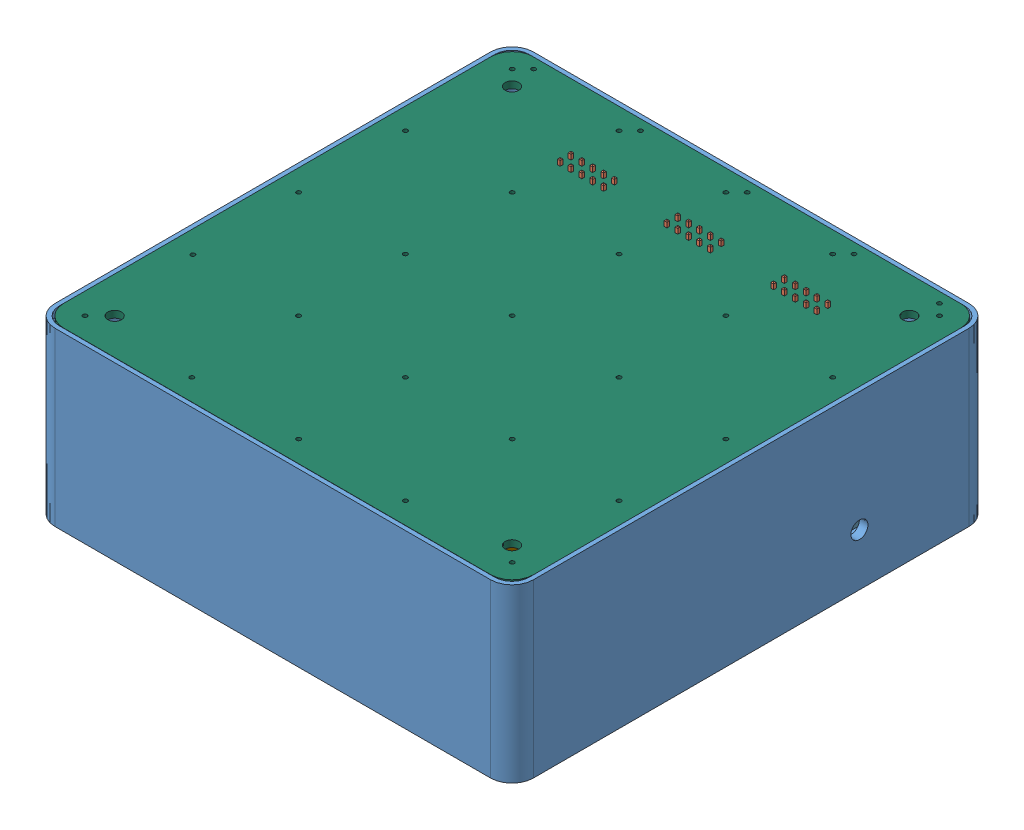
SolidWorks assembly Assembly_final, configuration Default. Lengths in mm.
Overall size (112 41.55 112).
151 component instances, 15 part files, 5 mates.
Components (placement in the parent):
- Enclosure_final-1: Enclosure_final [Default] at (47.994 33.4728 84.6976) size (112 40.2 112)
- LED_Cube_5X5X5.step-1: LED_Cube_5X5X5.step [Default] at (151.994 40.4728 -67.3024) x (0 0 1) z (0 1 0) size (100 101 23.3)
  - IDC-Header_2x05_P2.54mm_Vertical.step-1: IDC-Header_2x05_P2.54mm_Vertical.step [Default] at (191.25 -123 1.65) size (9.1 20.36 12.1)
    - SOLID.step-1: SOLID.step [Default] at origin size (9.1 20.36 12.1)
  - 61201023021_(rev1).step-1: 61201023021_(rev1).step [Default] at (192.25 -128 11.15) x (0 1 0) z (0 0 -1) size (17.38 6.86 15.7)
    - COMPOUND.step-1: COMPOUND.step [Default] at origin size (17.38 6.86 15.7)
  - C_Disc_D3.0mm_W1.6mm_P2.50mm.step-1: C_Disc_D3.0mm_W1.6mm_P2.50mm.step [Default] at (110.5 -105.5 1.65) x (-1 0 0) z (0 0 1) size (3.5 1.6 5.1)
    - SOLID-0.step-1: SOLID-0.step [Default] at origin size (3.5 1.6 5.1)
  - C_Disc_D3.0mm_W1.6mm_P2.50mm.step-2: C_Disc_D3.0mm_W1.6mm_P2.50mm.step [Default] at (110.5 -100.62 1.65) x (-1 0 0) z (0 0 1) size (3.5 1.6 5.1)
    - SOLID-0.step-1: SOLID-0.step [Default] at origin size (3.5 1.6 5.1)
  - CP_Radial_Tantal_D5.0mm_P5.00mm.step-1: CP_Radial_Tantal_D5.0mm_P5.00mm.step [Default] at (114 -90 1.65) x (0 -1 0) z (0 0 1) size (6 5 10.1)
    - SOLID-1.step-1: SOLID-1.step [Default] at origin size (6 5 10.1)
  - CP_Radial_Tantal_D5.0mm_P5.00mm.step-2: CP_Radial_Tantal_D5.0mm_P5.00mm.step [Default] at (153.75 -61.45 1.65) x (0 -1 0) z (0 0 1) size (6 5 10.1)
    - SOLID-1.step-1: SOLID-1.step [Default] at origin size (6 5 10.1)
  - CP_Radial_Tantal_D5.0mm_P5.00mm.step-3: CP_Radial_Tantal_D5.0mm_P5.00mm.step [Default] at (153.75 -87.2 1.65) x (0 -1 0) z (0 0 1) size (6 5 10.1)
    - SOLID-1.step-1: SOLID-1.step [Default] at origin size (6 5 10.1)
  - CP_Radial_Tantal_D5.0mm_P5.00mm.step-4: CP_Radial_Tantal_D5.0mm_P5.00mm.step [Default] at (153.75 -112.95 1.65) x (0 -1 0) z (0 0 1) size (6 5 10.1)
    - SOLID-1.step-1: SOLID-1.step [Default] at origin size (6 5 10.1)
  - CP_Radial_Tantal_D5.0mm_P5.00mm.step-5: CP_Radial_Tantal_D5.0mm_P5.00mm.step [Default] at (153.75 -138.2 1.65) x (0 -1 0) z (0 0 1) size (6 5 10.1)
    - SOLID-1.step-1: SOLID-1.step [Default] at origin size (6 5 10.1)
  - K375A_-PCM_DC_Power_Jack_2mm_Pin.step-1: K375A_-PCM_DC_Power_Jack_2mm_Pin.step [Default] at (108.0498 -117.25 1.65) x (0 1 0) z (0 0 1) size (9.8 14.5 16.1)
    - SOLID-2.step-1: SOLID-2.step [Default] at origin size (9.8 14.5 16.1)
  - TO-92_Inline.step-1: TO-92_Inline.step [Default] at (112.25 -143.25 1.65) x (0 1 0) z (0 0 1) size (4.83 3.75 9.8)
    - SOLID-3.step-1: SOLID-3.step [Default] at origin size (4.83 3.75 9.8)
  - TO-92_Inline.step-2: TO-92_Inline.step [Default] at (118.75 -143.25 1.65) x (0 1 0) z (0 0 1) size (4.83 3.75 9.8)
    - SOLID-3.step-1: SOLID-3.step [Default] at origin size (4.83 3.75 9.8)
  - TO-92_Inline.step-3: TO-92_Inline.step [Default] at (125.25 -143.25 1.65) x (0 1 0) z (0 0 1) size (4.83 3.75 9.8)
    - SOLID-3.step-1: SOLID-3.step [Default] at origin size (4.83 3.75 9.8)
  - TO-92_Inline.step-4: TO-92_Inline.step [Default] at (131.75 -143.25 1.65) x (0 1 0) z (0 0 1) size (4.83 3.75 9.8)
    - SOLID-3.step-1: SOLID-3.step [Default] at origin size (4.83 3.75 9.8)
  - TO-92_Inline.step-5: TO-92_Inline.step [Default] at (138.25 -143.25 1.65) x (0 1 0) z (0 0 1) size (4.83 3.75 9.8)
    - SOLID-3.step-1: SOLID-3.step [Default] at origin size (4.83 3.75 9.8)
  - R_Axial_DIN0207_L6.3mm_D2.5mm_P7.62mm_Horizontal.step-1: R_Axial_DIN0207_L6.3mm_D2.5mm_P7.62mm_Horizontal.step [Default] at (130.5 -69 1.65) x (-1 0 0) z (0 0 1) size (8.22 2.5 5.5)
    - SOLID-4.step-1: SOLID-4.step [Default] at origin size (8.22 2.5 5.5)
  - R_Axial_DIN0207_L6.3mm_D2.5mm_P7.62mm_Horizontal.step-2: R_Axial_DIN0207_L6.3mm_D2.5mm_P7.62mm_Horizontal.step [Default] at (148 -60.14 1.65) x (0 -1 0) z (0 0 1) size (8.22 2.5 5.5)
    - SOLID-4.step-1: SOLID-4.step [Default] at origin size (8.22 2.5 5.5)
  - R_Axial_DIN0207_L6.3mm_D2.5mm_P7.62mm_Horizontal.step-3: R_Axial_DIN0207_L6.3mm_D2.5mm_P7.62mm_Horizontal.step [Default] at (113.9722 -135.5 1.65) x (0 1 0) z (0 0 1) size (8.22 2.5 5.5)
    - SOLID-4.step-1: SOLID-4.step [Default] at origin size (8.22 2.5 5.5)
  - R_Axial_DIN0207_L6.3mm_D2.5mm_P7.62mm_Horizontal.step-4: R_Axial_DIN0207_L6.3mm_D2.5mm_P7.62mm_Horizontal.step [Default] at (120.4167 -135.5 1.65) x (0 1 0) z (0 0 1) size (8.22 2.5 5.5)
    - SOLID-4.step-1: SOLID-4.step [Default] at origin size (8.22 2.5 5.5)
  - R_Axial_DIN0207_L6.3mm_D2.5mm_P7.62mm_Horizontal.step-5: R_Axial_DIN0207_L6.3mm_D2.5mm_P7.62mm_Horizontal.step [Default] at (126.8611 -135.5 1.65) x (0 1 0) z (0 0 1) size (8.22 2.5 5.5)
    - SOLID-4.step-1: SOLID-4.step [Default] at origin size (8.22 2.5 5.5)
  - R_Axial_DIN0207_L6.3mm_D2.5mm_P7.62mm_Horizontal.step-6: R_Axial_DIN0207_L6.3mm_D2.5mm_P7.62mm_Horizontal.step [Default] at (133.3056 -135.5 1.65) x (0 1 0) z (0 0 1) size (8.22 2.5 5.5)
    - SOLID-4.step-1: SOLID-4.step [Default] at origin size (8.22 2.5 5.5)
  - R_Axial_DIN0207_L6.3mm_D2.5mm_P7.62mm_Horizontal.step-7: R_Axial_DIN0207_L6.3mm_D2.5mm_P7.62mm_Horizontal.step [Default] at (139.75 -135.5 1.65) x (0 1 0) z (0 0 1) size (8.22 2.5 5.5)
    - SOLID-4.step-1: SOLID-4.step [Default] at origin size (8.22 2.5 5.5)
  - R_Axial_DIN0207_L6.3mm_D2.5mm_P7.62mm_Horizontal.step-8: R_Axial_DIN0207_L6.3mm_D2.5mm_P7.62mm_Horizontal.step [Default] at (110.75 -127.88 1.65) x (0 -1 0) z (0 0 1) size (8.22 2.5 5.5)
    - SOLID-4.step-1: SOLID-4.step [Default] at origin size (8.22 2.5 5.5)
  - R_Axial_DIN0207_L6.3mm_D2.5mm_P7.62mm_Horizontal.step-9: R_Axial_DIN0207_L6.3mm_D2.5mm_P7.62mm_Horizontal.step [Default] at (117.1944 -127.88 1.65) x (0 -1 0) z (0 0 1) size (8.22 2.5 5.5)
    - SOLID-4.step-1: SOLID-4.step [Default] at origin size (8.22 2.5 5.5)
  - R_Axial_DIN0207_L6.3mm_D2.5mm_P7.62mm_Horizontal.step-10: R_Axial_DIN0207_L6.3mm_D2.5mm_P7.62mm_Horizontal.step [Default] at (123.6389 -127.88 1.65) x (0 -1 0) z (0 0 1) size (8.22 2.5 5.5)
    - SOLID-4.step-1: SOLID-4.step [Default] at origin size (8.22 2.5 5.5)
  - R_Axial_DIN0207_L6.3mm_D2.5mm_P7.62mm_Horizontal.step-11: R_Axial_DIN0207_L6.3mm_D2.5mm_P7.62mm_Horizontal.step [Default] at (130.0833 -127.88 1.65) x (0 -1 0) z (0 0 1) size (8.22 2.5 5.5)
    - SOLID-4.step-1: SOLID-4.step [Default] at origin size (8.22 2.5 5.5)
  - R_Axial_DIN0207_L6.3mm_D2.5mm_P7.62mm_Horizontal.step-12: R_Axial_DIN0207_L6.3mm_D2.5mm_P7.62mm_Horizontal.step [Default] at (136.5278 -127.88 1.65) x (0 -1 0) z (0 0 1) size (8.22 2.5 5.5)
    - SOLID-4.step-1: SOLID-4.step [Default] at origin size (8.22 2.5 5.5)
  - R_Axial_DIN0207_L6.3mm_D2.5mm_P7.62mm_Horizontal.step-13: R_Axial_DIN0207_L6.3mm_D2.5mm_P7.62mm_Horizontal.step [Default] at (157.5 -73 1.65) x (0 -1 0) z (0 0 1) size (8.22 2.5 5.5)
    - SOLID-4.step-1: SOLID-4.step [Default] at origin size (8.22 2.5 5.5)
  - R_Axial_DIN0207_L6.3mm_D2.5mm_P7.62mm_Horizontal.step-14: R_Axial_DIN0207_L6.3mm_D2.5mm_P7.62mm_Horizontal.step [Default] at (160.75 -73 1.65) x (0 -1 0) z (0 0 1) size (8.22 2.5 5.5)
    - SOLID-4.step-1: SOLID-4.step [Default] at origin size (8.22 2.5 5.5)
  - R_Axial_DIN0207_L6.3mm_D2.5mm_P7.62mm_Horizontal.step-15: R_Axial_DIN0207_L6.3mm_D2.5mm_P7.62mm_Horizontal.step [Default] at (164 -73 1.65) x (0 -1 0) z (0 0 1) size (8.22 2.5 5.5)
    - SOLID-4.step-1: SOLID-4.step [Default] at origin size (8.22 2.5 5.5)
  - R_Axial_DIN0207_L6.3mm_D2.5mm_P7.62mm_Horizontal.step-16: R_Axial_DIN0207_L6.3mm_D2.5mm_P7.62mm_Horizontal.step [Default] at (167.25 -73 1.65) x (0 -1 0) z (0 0 1) size (8.22 2.5 5.5)
    - SOLID-4.step-1: SOLID-4.step [Default] at origin size (8.22 2.5 5.5)
  - R_Axial_DIN0207_L6.3mm_D2.5mm_P7.62mm_Horizontal.step-17: R_Axial_DIN0207_L6.3mm_D2.5mm_P7.62mm_Horizontal.step [Default] at (170.5 -73 1.65) x (0 -1 0) z (0 0 1) size (8.22 2.5 5.5)
    - SOLID-4.step-1: SOLID-4.step [Default] at origin size (8.22 2.5 5.5)
  - R_Axial_DIN0207_L6.3mm_D2.5mm_P7.62mm_Horizontal.step-18: R_Axial_DIN0207_L6.3mm_D2.5mm_P7.62mm_Horizontal.step [Default] at (173.75 -73 1.65) x (0 -1 0) z (0 0 1) size (8.22 2.5 5.5)
    - SOLID-4.step-1: SOLID-4.step [Default] at origin size (8.22 2.5 5.5)
  - R_Axial_DIN0207_L6.3mm_D2.5mm_P7.62mm_Horizontal.step-19: R_Axial_DIN0207_L6.3mm_D2.5mm_P7.62mm_Horizontal.step [Default] at (177 -73 1.65) x (0 -1 0) z (0 0 1) size (8.22 2.5 5.5)
    - SOLID-4.step-1: SOLID-4.step [Default] at origin size (8.22 2.5 5.5)
  - R_Axial_DIN0207_L6.3mm_D2.5mm_P7.62mm_Horizontal.step-20: R_Axial_DIN0207_L6.3mm_D2.5mm_P7.62mm_Horizontal.step [Default] at (180.25 -73 1.65) x (0 -1 0) z (0 0 1) size (8.22 2.5 5.5)
    - SOLID-4.step-1: SOLID-4.step [Default] at origin size (8.22 2.5 5.5)
  - R_Axial_DIN0207_L6.3mm_D2.5mm_P7.62mm_Horizontal.step-21: R_Axial_DIN0207_L6.3mm_D2.5mm_P7.62mm_Horizontal.step [Default] at (148 -85.89 1.65) x (0 -1 0) z (0 0 1) size (8.22 2.5 5.5)
    - SOLID-4.step-1: SOLID-4.step [Default] at origin size (8.22 2.5 5.5)
  - R_Axial_DIN0207_L6.3mm_D2.5mm_P7.62mm_Horizontal.step-22: R_Axial_DIN0207_L6.3mm_D2.5mm_P7.62mm_Horizontal.step [Default] at (157.5 -98.75 1.65) x (0 -1 0) z (0 0 1) size (8.22 2.5 5.5)
    - SOLID-4.step-1: SOLID-4.step [Default] at origin size (8.22 2.5 5.5)
  - R_Axial_DIN0207_L6.3mm_D2.5mm_P7.62mm_Horizontal.step-23: R_Axial_DIN0207_L6.3mm_D2.5mm_P7.62mm_Horizontal.step [Default] at (160.75 -98.75 1.65) x (0 -1 0) z (0 0 1) size (8.22 2.5 5.5)
    - SOLID-4.step-1: SOLID-4.step [Default] at origin size (8.22 2.5 5.5)
  - R_Axial_DIN0207_L6.3mm_D2.5mm_P7.62mm_Horizontal.step-24: R_Axial_DIN0207_L6.3mm_D2.5mm_P7.62mm_Horizontal.step [Default] at (164 -98.75 1.65) x (0 -1 0) z (0 0 1) size (8.22 2.5 5.5)
    - SOLID-4.step-1: SOLID-4.step [Default] at origin size (8.22 2.5 5.5)
  - R_Axial_DIN0207_L6.3mm_D2.5mm_P7.62mm_Horizontal.step-25: R_Axial_DIN0207_L6.3mm_D2.5mm_P7.62mm_Horizontal.step [Default] at (167.25 -98.75 1.65) x (0 -1 0) z (0 0 1) size (8.22 2.5 5.5)
    - SOLID-4.step-1: SOLID-4.step [Default] at origin size (8.22 2.5 5.5)
  - R_Axial_DIN0207_L6.3mm_D2.5mm_P7.62mm_Horizontal.step-26: R_Axial_DIN0207_L6.3mm_D2.5mm_P7.62mm_Horizontal.step [Default] at (170.5 -98.75 1.65) x (0 -1 0) z (0 0 1) size (8.22 2.5 5.5)
    - SOLID-4.step-1: SOLID-4.step [Default] at origin size (8.22 2.5 5.5)
  - R_Axial_DIN0207_L6.3mm_D2.5mm_P7.62mm_Horizontal.step-27: R_Axial_DIN0207_L6.3mm_D2.5mm_P7.62mm_Horizontal.step [Default] at (173.75 -98.75 1.65) x (0 -1 0) z (0 0 1) size (8.22 2.5 5.5)
    - SOLID-4.step-1: SOLID-4.step [Default] at origin size (8.22 2.5 5.5)
  - R_Axial_DIN0207_L6.3mm_D2.5mm_P7.62mm_Horizontal.step-28: R_Axial_DIN0207_L6.3mm_D2.5mm_P7.62mm_Horizontal.step [Default] at (177 -98.75 1.65) x (0 -1 0) z (0 0 1) size (8.22 2.5 5.5)
    - SOLID-4.step-1: SOLID-4.step [Default] at origin size (8.22 2.5 5.5)
  - R_Axial_DIN0207_L6.3mm_D2.5mm_P7.62mm_Horizontal.step-29: R_Axial_DIN0207_L6.3mm_D2.5mm_P7.62mm_Horizontal.step [Default] at (180.25 -98.75 1.65) x (0 -1 0) z (0 0 1) size (8.22 2.5 5.5)
    - SOLID-4.step-1: SOLID-4.step [Default] at origin size (8.22 2.5 5.5)
  - R_Axial_DIN0207_L6.3mm_D2.5mm_P7.62mm_Horizontal.step-30: R_Axial_DIN0207_L6.3mm_D2.5mm_P7.62mm_Horizontal.step [Default] at (148 -111.64 1.65) x (0 -1 0) z (0 0 1) size (8.22 2.5 5.5)
    - SOLID-4.step-1: SOLID-4.step [Default] at origin size (8.22 2.5 5.5)
  - R_Axial_DIN0207_L6.3mm_D2.5mm_P7.62mm_Horizontal.step-31: R_Axial_DIN0207_L6.3mm_D2.5mm_P7.62mm_Horizontal.step [Default] at (157.5 -124.25 1.65) x (0 -1 0) z (0 0 1) size (8.22 2.5 5.5)
    - SOLID-4.step-1: SOLID-4.step [Default] at origin size (8.22 2.5 5.5)
  - R_Axial_DIN0207_L6.3mm_D2.5mm_P7.62mm_Horizontal.step-32: R_Axial_DIN0207_L6.3mm_D2.5mm_P7.62mm_Horizontal.step [Default] at (160.75 -124.25 1.65) x (0 -1 0) z (0 0 1) size (8.22 2.5 5.5)
    - SOLID-4.step-1: SOLID-4.step [Default] at origin size (8.22 2.5 5.5)
  - R_Axial_DIN0207_L6.3mm_D2.5mm_P7.62mm_Horizontal.step-33: R_Axial_DIN0207_L6.3mm_D2.5mm_P7.62mm_Horizontal.step [Default] at (164 -124.25 1.65) x (0 -1 0) z (0 0 1) size (8.22 2.5 5.5)
    - SOLID-4.step-1: SOLID-4.step [Default] at origin size (8.22 2.5 5.5)
  - R_Axial_DIN0207_L6.3mm_D2.5mm_P7.62mm_Horizontal.step-34: R_Axial_DIN0207_L6.3mm_D2.5mm_P7.62mm_Horizontal.step [Default] at (167.25 -124.25 1.65) x (0 -1 0) z (0 0 1) size (8.22 2.5 5.5)
    - SOLID-4.step-1: SOLID-4.step [Default] at origin size (8.22 2.5 5.5)
  - R_Axial_DIN0207_L6.3mm_D2.5mm_P7.62mm_Horizontal.step-35: R_Axial_DIN0207_L6.3mm_D2.5mm_P7.62mm_Horizontal.step [Default] at (170.5 -124.25 1.65) x (0 -1 0) z (0 0 1) size (8.22 2.5 5.5)
    - SOLID-4.step-1: SOLID-4.step [Default] at origin size (8.22 2.5 5.5)
  - R_Axial_DIN0207_L6.3mm_D2.5mm_P7.62mm_Horizontal.step-36: R_Axial_DIN0207_L6.3mm_D2.5mm_P7.62mm_Horizontal.step [Default] at (173.75 -124.25 1.65) x (0 -1 0) z (0 0 1) size (8.22 2.5 5.5)
    - SOLID-4.step-1: SOLID-4.step [Default] at origin size (8.22 2.5 5.5)
  - R_Axial_DIN0207_L6.3mm_D2.5mm_P7.62mm_Horizontal.step-37: R_Axial_DIN0207_L6.3mm_D2.5mm_P7.62mm_Horizontal.step [Default] at (177 -124.25 1.65) x (0 -1 0) z (0 0 1) size (8.22 2.5 5.5)
    - SOLID-4.step-1: SOLID-4.step [Default] at origin size (8.22 2.5 5.5)
  - R_Axial_DIN0207_L6.3mm_D2.5mm_P7.62mm_Horizontal.step-38: R_Axial_DIN0207_L6.3mm_D2.5mm_P7.62mm_Horizontal.step [Default] at (180.25 -124.25 1.65) x (0 -1 0) z (0 0 1) size (8.22 2.5 5.5)
    - SOLID-4.step-1: SOLID-4.step [Default] at origin size (8.22 2.5 5.5)
  - R_Axial_DIN0207_L6.3mm_D2.5mm_P7.62mm_Horizontal.step-39: R_Axial_DIN0207_L6.3mm_D2.5mm_P7.62mm_Horizontal.step [Default] at (182 -144.51 1.65) x (0 1 0) z (0 0 1) size (8.22 2.5 5.5)
    - SOLID-4.step-1: SOLID-4.step [Default] at origin size (8.22 2.5 5.5)
  - R_Axial_DIN0207_L6.3mm_D2.5mm_P7.62mm_Horizontal.step-40: R_Axial_DIN0207_L6.3mm_D2.5mm_P7.62mm_Horizontal.step [Default] at (148 -136.89 1.65) x (0 -1 0) z (0 0 1) size (8.22 2.5 5.5)
    - SOLID-4.step-1: SOLID-4.step [Default] at origin size (8.22 2.5 5.5)
  - DIP-16_on_SCSM-16.step-1: DIP-16_on_SCSM-16.step [Default] at (160 -67.75 1.65) size (20.32 10.16 11)
    - COMPOUND-5.step-1: COMPOUND-5.step [Default] at origin size (20.32 10.16 11)
  - DIP-16_on_SCSM-16.step-2: DIP-16_on_SCSM-16.step [Default] at (160 -93.5 1.65) size (20.32 10.16 11)
    - COMPOUND-5.step-1: COMPOUND-5.step [Default] at origin size (20.32 10.16 11)
  - DIP-16_on_SCSM-16.step-3: DIP-16_on_SCSM-16.step [Default] at (160 -119.25 1.65) size (20.32 10.16 11)
    - COMPOUND-5.step-1: COMPOUND-5.step [Default] at origin size (20.32 10.16 11)
  - DIP-16_on_SCSM-16.step-4: DIP-16_on_SCSM-16.step [Default] at (160 -144.5 1.65) size (20.32 10.16 11)
    - COMPOUND-5.step-1: COMPOUND-5.step [Default] at origin size (20.32 10.16 11)
  - Crystal_HC49-4H_Vertical.step-1: Crystal_HC49-4H_Vertical.step [Default] at (115.5 -105.5 1.65) x (0 1 0) z (0 0 1) size (11.05 4.65 7)
    - SOLID-6.step-1: SOLID-6.step [Default] at origin size (11.05 4.65 7)
  - DIP-40-W_on_SCLM-40.step-1: DIP-40-W_on_SCLM-40.step [Default] at (121.25 -74 1.65) x (0 -1 0) z (0 0 1) size (50.8 17.78 11)
    - COMPOUND-7.step-1: COMPOUND-7.step [Default] at origin size (50.8 17.78 11)
  - IDC-Header_2x05_P2.54mm_Horizontal.step-1: IDC-Header_2x05_P2.54mm_Horizontal.step [Default] at (115.5 -84.5 1.65) x (-1 0 0) z (0 0 1) size (13.55 20.36 12.1)
    - SOLID-8.step-1: SOLID-8.step [Default] at origin size (13.55 20.36 12.1)
  - IDC-Header_2x05_P2.54mm_Vertical.step-2: IDC-Header_2x05_P2.54mm_Vertical.step [Default] at (191.25 -80 1.65) size (9.1 20.36 12.1)
    - SOLID.step-1: SOLID.step [Default] at origin size (9.1 20.36 12.1)
  - 61201023021_(rev1).step-2: 61201023021_(rev1).step [Default] at (192.25 -85 11.15) x (0 1 0) z (0 0 -1) size (17.38 6.86 15.7)
    - COMPOUND.step-1: COMPOUND.step [Default] at origin size (17.38 6.86 15.7)
  - IDC-Header_2x05_P2.54mm_Vertical.step-3: IDC-Header_2x05_P2.54mm_Vertical.step [Default] at (191.25 -101.5 1.65) size (9.1 20.36 12.1)
    - SOLID.step-1: SOLID.step [Default] at origin size (9.1 20.36 12.1)
  - 61201023021_(rev1).step-3: 61201023021_(rev1).step [Default] at (192.25 -106.5 11.15) x (0 1 0) z (0 0 -1) size (17.38 6.86 15.7)
    - COMPOUND.step-1: COMPOUND.step [Default] at origin size (17.38 6.86 15.7)
  - SW_Tactile_SPST_Angled_PTS645Vx39-2LFS.step-1: SW_Tactile_SPST_Angled_PTS645Vx39-2LFS.step [Default] at (124.415 -56.75 1.65) size (7.4 7.9 11)
    - SOLID-9.step-1: SOLID-9.step [Default] at origin size (7.4 7.9 11)
  - COMPOUND-10.step-1: COMPOUND-10.step [Default] at origin size (100 100 1.6)
- LED_Cube_5X5X5_PCB2.step-1: LED_Cube_5X5X5_PCB2.step [Default] at (140.994 72.0728 -64.6024) x (0 0 1) z (0 1 0) size (110 110 22.2)
  - PinHeader_2x05_P2.54mm_Vertical_SMD.step-1: PinHeader_2x05_P2.54mm_Vertical_SMD.step [Default] at (110.55 -68 -0.05) x (1 0 0) z (0 0 -1) size (9.1 20.36 12.1)
    - SOLID.step-1: SOLID.step [Default] at origin size (9.1 20.36 12.1)
  - 61201023021_(rev1).step-1: 61201023021_(rev1).step [Default] at (110.55 -68 -10.55) x (0 1 0) z (0 0 1) size (17.38 6.86 15.7)
    - COMPOUND.step-1: COMPOUND.step [Default] at origin size (17.38 6.86 15.7)
  - PinHeader_2x05_P2.54mm_Vertical_SMD.step-2: PinHeader_2x05_P2.54mm_Vertical_SMD.step [Default] at (110.5 -93 -0.05) x (1 0 0) z (0 0 -1) size (9.1 20.36 12.1)
    - SOLID.step-1: SOLID.step [Default] at origin size (9.1 20.36 12.1)
  - 61201023021_(rev1).step-2: 61201023021_(rev1).step [Default] at (110.5 -93 -10.55) x (0 1 0) z (0 0 1) size (17.38 6.86 15.7)
    - COMPOUND.step-1: COMPOUND.step [Default] at origin size (17.38 6.86 15.7)
  - PinHeader_2x05_P2.54mm_Vertical_SMD.step-3: PinHeader_2x05_P2.54mm_Vertical_SMD.step [Default] at (110.5 -118 -0.05) x (1 0 0) z (0 0 -1) size (9.1 20.36 12.1)
    - SOLID.step-1: SOLID.step [Default] at origin size (9.1 20.36 12.1)
  - 61201023021_(rev1).step-3: 61201023021_(rev1).step [Default] at (110.5 -118 -10.55) x (0 1 0) z (0 0 1) size (17.38 6.86 15.7)
    - COMPOUND.step-1: COMPOUND.step [Default] at origin size (17.38 6.86 15.7)
  - COMPOUND-0.step-1: COMPOUND-0.step [Default] at origin size (110 110 1.6)
Mates (geometry in assembly coordinates):
- Coincident1: coincident anti-aligned: circle of kuciste-1; circle of LED_Cube_5X5X5.step-1/COMPOUND-10.step-1
- Coincident2: coincident anti-aligned: circle of kuciste-1; circle of LED_Cube_5X5X5.step-1/COMPOUND-10.step-1
- Coincident18: coincident anti-aligned: plane of kuciste-1 through (-3.006 72.0728 135.6976) normal (0 1 0); plane of LED_Cube_5X5X5_PCB2.step-1/COMPOUND-0.step-1 through (47.994 72.0728 84.6476) normal (0 -1 0)
- Concentric3: concentric aligned: circle of LED_Cube_5X5X5.step-1/COMPOUND-10.step-1; circle of LED_Cube_5X5X5_PCB2.step-1/COMPOUND-0.step-1
- Concentric4: concentric aligned: circle of LED_Cube_5X5X5.step-1/COMPOUND-10.step-1; circle of LED_Cube_5X5X5_PCB2.step-1/COMPOUND-0.step-1
